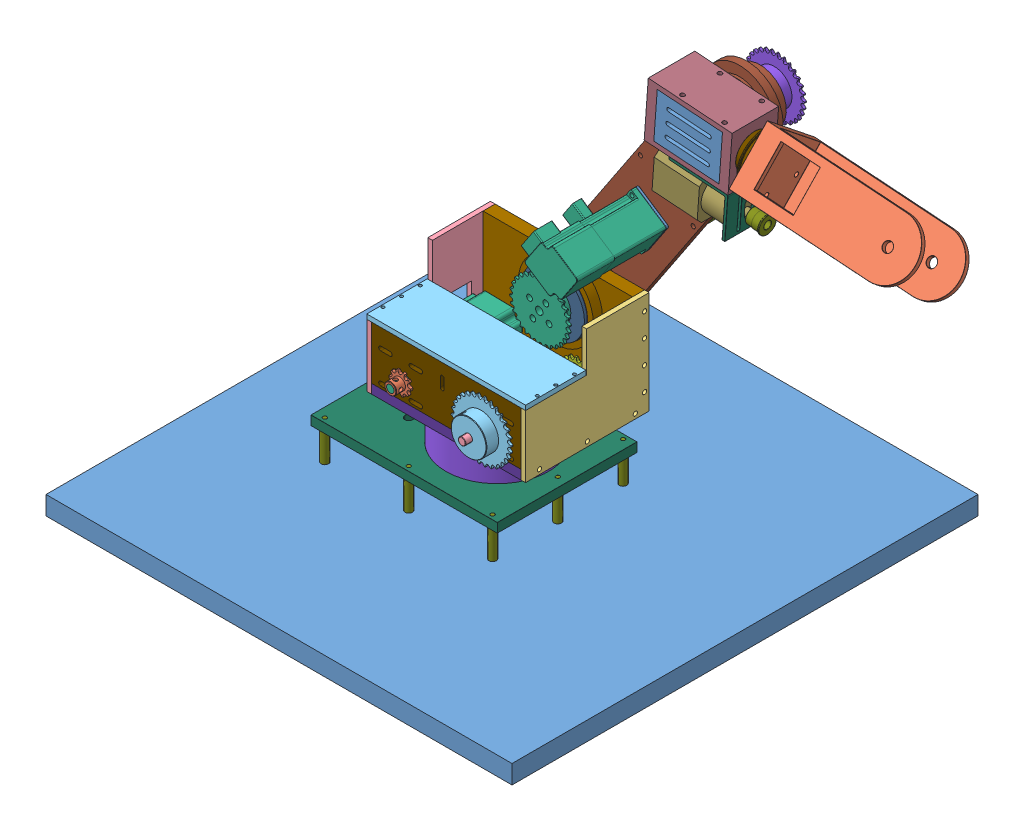
SolidWorks assembly joint 1 assembly, configuration Default. Lengths in mm.
Overall size (663.35 621.65 500).
151 component instances, 59 part files, 55 mates.
Components (placement in the parent):
- base wood-1: base wood [Default] at (212.0824 390.1321 436.9569) size (500 20 500)
- gear hold on joint 1-1: gear hold on joint 1 [Default] at (112.0824 407.1321 436.9569) x (-0.002512 0 0.999997) z (-0.999997 0 -0.002512) size (42 3 42)
- gear100w_cylinder-1: gear100w_cylinder [Default] at (112.0824 385.1321 436.9569) x (0.951917 0 -0.306357) z (0.306357 0 0.951917) size (14 51 14)
- Base holding motor-1: Base holding motor [Default] at (112.0824 410.1321 436.9569) size (70 5 62)
- gear servo 100W-1: gear servo 100W [Default] at (112.0824 407.1321 436.9569) x (-0.002512 0 0.999997) z (-0.999997 0 -0.002512) size (42 67 42)
- mitsu 100W motor-1: mitsu 100W motor [Default] at (92.1327 338.1321 416.9067) x (-0.002512 0 0.999997) z (-0.999997 0 -0.002512) size (42 121 56)
- 15teeths_14mm-1: 15teeths_14mm [25B15] at (112.0824 436.1321 436.9569) size (33.63 12.7 33.47)
- turret cover-1: turret cover [Default] at (196.2679 462.6321 436.9569) size (110 41 110)
- 51113-1: 51113 [Default] at (196.2679 474.1321 436.9569) x (0.999998 0 -0.002197) z (0.002197 0 0.999998) size (90 18 90)
  - 51113_3-1: 51113_3 [Default] at (-36.8829 9 -13.4243) x (0 -1 0) z (0 0 1) size (9 9 9)
  - 51113_3-2: 51113_3 [Default] at (-30.0672 9 -25.2294) x (0 -1 0) z (0 0 1) size (9 9 9)
  - 51113_3-3: 51113_3 [Default] at (-19.625 9 -33.9915) x (0 -1 0) z (0 0 1) size (9 9 9)
  - 51113_3-4: 51113_3 [Default] at (-6.8157 9 -38.6537) x (0 -1 0) z (0 0 1) size (9 9 9)
  - 51113_3-5: 51113_3 [Default] at (6.8157 9 -38.6537) x (0 -1 0) z (0 0 1) size (9 9 9)
  - 51113_3-6: 51113_3 [Default] at (19.625 9 -33.9915) x (0 -1 0) z (0 0 1) size (9 9 9)
  - 51113_3-7: 51113_3 [Default] at (30.0672 9 -25.2294) x (0 -1 0) z (0 0 1) size (9 9 9)
  - 51113_3-8: 51113_3 [Default] at (36.8829 9 -13.4243) x (0 -1 0) z (0 0 1) size (9 9 9)
  - 51113_3-9: 51113_3 [Default] at (39.25 9 0) x (0 -1 0) z (0 0 1) size (9 9 9)
  - 51113_3-10: 51113_3 [Default] at (36.8829 9 13.4243) x (0 -1 0) z (0 0 1) size (9 9 9)
  - 51113_3-11: 51113_3 [Default] at (30.0672 9 25.2294) x (0 -1 0) z (0 0 1) size (9 9 9)
  - 51113_3-12: 51113_3 [Default] at (19.625 9 33.9915) x (0 -1 0) z (0 0 1) size (9 9 9)
  - 51113_3-13: 51113_3 [Default] at (6.8157 9 38.6537) x (0 -1 0) z (0 0 1) size (9 9 9)
  - 51113_3-14: 51113_3 [Default] at (-6.8157 9 38.6537) x (0 -1 0) z (0 0 1) size (9 9 9)
  - 51113_3-15: 51113_3 [Default] at (-19.625 9 33.9915) x (0 -1 0) z (0 0 1) size (9 9 9)
  - 51113_3-16: 51113_3 [Default] at (-30.0672 9 25.2294) x (0 -1 0) z (0 0 1) size (9 9 9)
  - 51113_3-17: 51113_3 [Default] at (-36.8829 9 13.4243) x (0 -1 0) z (0 0 1) size (9 9 9)
  - 51113_3-18: 51113_3 [Default] at (-39.25 9 0) x (0 -1 0) z (0 0 1) size (9 9 9)
  - 51113_22-1: 51113_22 [Default] at (0 13 0) x (0 1 0) z (0 0 1) size (5 90 90)
  - 51113_24-1: 51113_24 [Default] at origin size (90 5 90)
- B6812VV-1: B6812VV [Default] at (196.2679 474.1321 436.9569) x (0 -1 0) z (1 0 0) size (10 78 78)
- B6812VV-2: B6812VV [Default] at (196.2679 451.1321 436.9569) x (0 1 0) z (0 0 1) size (10 78 78)
- joint 1 turret-1: joint 1 turret [Default] at (196.2679 451.1321 436.9569) x (0.160249 0 -0.987077) z (0 1 0) size (77 77 57)
- 45teeths_turret joint 1-1: 45teeths_turret joint 1 [25B45] at (196.2679 433.3381 436.9569) x (0.160249 0 -0.987077) z (-0.987077 0 -0.160249) size (94.59 2.79 94.53)
- Base Joint 1-1: Base Joint 1 [Default] at (196.2679 441.1321 436.9569) size (200 10 150)
- hold up base joint 1-1: hold up base joint 1 [Default] at (261.2679 410.1321 506.9569) size (8 61 8)
- hold up base joint 1-2: hold up base joint 1 [Default] at (171.2679 410.1321 366.9569) size (8 61 8)
- hold up base joint 1-3: hold up base joint 1 [Default] at (81.2679 410.1321 366.9569) size (8 61 8)
- hold up base joint 1-4: hold up base joint 1 [Default] at (171.2679 410.1321 506.9569) size (8 61 8)
- hold up base joint 1-5: hold up base joint 1 [Default] at (261.2679 410.1321 436.9569) size (8 61 8)
- hold up base joint 1-6: hold up base joint 1 [Default] at (261.2679 410.1321 366.9569) size (8 61 8)
- hold up base joint 1-7: hold up base joint 1 [Default] at (81.2679 410.1321 436.9569) size (8 61 8)
- hold up base joint 1-8: hold up base joint 1 [Default] at (81.2679 410.1321 506.9569) size (8 61 8)
- joint 2 assembly ver2 -1: joint 2 assembly ver2  [Default] at (57.2608 443.2302 488.4776) x (-0.002197 0 -0.999998) z (0.999998 0 -0.002197) size (231.98 388.16 503.96)
  - joint 1 turret cap-1: joint 1 turret cap [Default] at (51.2152 49.9019 139.1199) size (130 15 160)
  - hold servo and gear-1: hold servo and gear [Default] at (-13.7848 80.9681 149.1199) x (0 0 -1) z (0 -1 0) size (160 5 57.13)
  - mitsu 100W motor-1: mitsu 100W motor [Default] at (-0.7848 101.743 86.2077) x (0 -0.999767 -0.0216) z (0 0.0216 -0.999767) size (42 121 56)
  - on the servo 200W-1: on the servo 200W [Default] at (-8.7848 81.3156 105.771) x (0 0.0216 -0.999767) z (0 -0.999767 -0.0216) size (40 3 40)
  - 25B10 fixed-1: 25B10 fixed [25B10] at (-17.5848 81.3156 105.771) x (0 0.053959 -0.998543) z (0 -0.998543 -0.053959) size (23.35 12.7 22.79)
  - gear 100W-1: gear 100W [Default] at (55.2152 81.0007 192.7913) x (0 0 -1) z (0 -1 0) size (42 67 42)
  - long cylinder-1: long cylinder [Default] at (-0.7848 81.0007 192.7913) x (0 -0.902756 0.430154) z (0 -0.430154 -0.902756) size (14 125 14)
  - SP25B30 fixede-1: SP25B30 fixede [25B30] at (-17.5848 81.0007 192.7913) x (0 -0.851981 0.523572) z (0 0.523572 0.851981) size (64.23 15.88 63.98)
  - 15teeths_14mm-1: 15teeths_14mm [25B15] at (84.2152 81.0007 192.7913) x (0 -0.225508 -0.974241) z (0 -0.974241 0.225508) size (33.63 12.7 33.47)
  - 30teeths_turret-1: 30teeths_turret [25B30] at (78.4212 124.9019 157.0409) x (0 -0.554392 0.832255) z (0 -0.832255 -0.554392) size (64.23 14.79 63.98)
  - HR32909J-1: HR32909J [Default] at (96.2152 124.9019 157.0409) x (-1 0 0) z (0 -1 0) size (15 68 68)
    - HR32909J_3-1: HR32909J_3 [Default] at origin size (12 68 68)
    - HR32909J_5-1: HR32909J_5 [Default] at origin size (15 63.56 63.56)
  - HR32909J-2: HR32909J [Default] at (128.2152 124.9019 157.0409) size (15 68 68)
    - HR32909J_3-1: HR32909J_3 [Default] at origin size (12 68 68)
    - HR32909J_5-1: HR32909J_5 [Default] at origin size (15 63.56 63.56)
  - turret cover joint 2-2: turret cover joint 2 [Default] at (111.2152 124.9019 157.0409) x (0 0 1) z (0 -1 0) size (160 31 115)
  - Joint2 turret-2: Joint2 turret [Default] at (132.2152 124.9019 157.0409) x (0 0.832255 0.554392) z (-1 0 0) size (67 67 39)
  - joint 2 arm-2: joint 2 arm [Default] at (137.2152 124.9019 157.0409) x (0 0.832255 0.554392) z (0 -0.554392 0.832255) size (374 25 80)
  - mitsu 100W motor-2: mitsu 100W motor [Default] at (121.2152 210.8927 190.2911) x (0 0.832255 0.554392) z (0 0.554392 -0.832255) size (42 121 56)
  - on the servo 200W-2: on the servo 200W [Default] at (129.2152 216.4499 218.0241) x (0 0.832255 0.554392) z (0 -0.554392 0.832255) size (40 3 40)
  - SP25B30 fixed with bearing-1: SP25B30 fixed with bearing [25B30] at (150.7152 278.8691 259.6035) x (0 0.696244 0.717805) z (0 -0.717805 0.696244) size (64.23 15.88 63.98)
  - 25B10 fixed-3: 25B10 fixed [25B10] at (172.2902 278.8691 259.6035) x (0 -0.696244 -0.717805) z (0 -0.717805 0.696244) size (23.35 12.7 22.79)
  - hold bearing tang dua-2: hold bearing tang dua [Default] at (129.2152 278.8691 259.6035) x (0 -0.832255 -0.554392) z (0 -0.554392 0.832255) size (30 8 30)
  - BB_688_B180_10_ES-1: BB_688_B180_10_ES [Default] at (153.2152 278.8691 259.6035) x (1 0 0) z (0 0.696244 0.717805) size (5 16 16)
    - BB_688_B180_10_ES_3-1: BB_688_B180_10_ES_3 [Default] at (0 3.7394 -4.689) x (-1 0 0) z (0 0 1) size (3 3 3)
    - BB_688_B180_10_ES_3-2: BB_688_B180_10_ES_3 [Default] at (0 -1.3346 -5.8471) x (-1 0 0) z (0 0 1) size (3 3 3)
    - BB_688_B180_10_ES_3-3: BB_688_B180_10_ES_3 [Default] at (0 -5.4036 -2.6022) x (-1 0 0) z (0 0 1) size (3 3 3)
    - BB_688_B180_10_ES_3-4: BB_688_B180_10_ES_3 [Default] at (0 -5.4036 2.6022) x (-1 0 0) z (0 0 1) size (3 3 3)
    - BB_688_B180_10_ES_3-5: BB_688_B180_10_ES_3 [Default] at (0 -1.3346 5.8471) x (-1 0 0) z (0 0 1) size (3 3 3)
    - BB_688_B180_10_ES_3-6: BB_688_B180_10_ES_3 [Default] at (0 3.7394 4.689) x (-1 0 0) z (0 0 1) size (3 3 3)
    - BB_688_B180_10_ES_3-7: BB_688_B180_10_ES_3 [Default] at (0 5.9975 0) x (-1 0 0) z (0 0 1) size (3 3 3)
    - BB_688_B180_10_ES_11-1: BB_688_B180_10_ES_11 [Default] x (1 0 0) z (0 -0.781831 0.62349) size (0.75 1.78 2.65)
    - BB_688_B180_10_ES_11-2: BB_688_B180_10_ES_11 [Default] x (1 0 0) z (0 -0.974928 -0.222521) size (0.75 1.78 2.65)
    - BB_688_B180_10_ES_11-3: BB_688_B180_10_ES_11 [Default] x (1 0 0) z (0 -0.433884 -0.900969) size (0.75 1.78 2.65)
    - BB_688_B180_10_ES_11-4: BB_688_B180_10_ES_11 [Default] x (1 0 0) z (0 0.433884 -0.900969) size (0.75 1.78 2.65)
    - BB_688_B180_10_ES_11-5: BB_688_B180_10_ES_11 [Default] x (1 0 0) z (0 0.974928 -0.222521) size (0.75 1.78 2.65)
    - BB_688_B180_10_ES_11-6: BB_688_B180_10_ES_11 [Default] x (1 0 0) z (0 0.781831 0.62349) size (0.75 1.78 2.65)
    - BB_688_B180_10_ES_11-7: BB_688_B180_10_ES_11 [Default] at origin size (0.75 1.78 2.65)
    - BB_688_B180_10_ES_19-1: BB_688_B180_10_ES_19 [Default] x (-1 0 0) z (0 0 1) size (5 10.66 10.66)
    - BB_688_B180_10_ES_21-1: BB_688_B180_10_ES_21 [Default] at origin size (5 16 16)
  - 608VV-3: 608VV [Default] at (122.2152 278.8691 259.6035) x (1 0 0) z (0 0.832255 0.554392) size (7 22 22)
    - 608VV_3-1: 608VV_3 [Default] at origin size (0.29 19 19)
    - 608VV_5-1: 608VV_5 [Default] at (3.5 5.3033 5.3033) x (1 0 0) z (0 -1 0) size (4.2 4.2 4.2)
    - 608VV_5-2: 608VV_5 [Default] at (3.5 7.5 0) x (1 0 0) z (0 -1 0) size (4.2 4.2 4.2)
    - 608VV_5-3: 608VV_5 [Default] at (3.5 5.3033 -5.3033) x (1 0 0) z (0 -1 0) size (4.2 4.2 4.2)
    - 608VV_5-4: 608VV_5 [Default] at (3.5 0 -7.5) x (1 0 0) z (0 -1 0) size (4.2 4.2 4.2)
    - 608VV_5-5: 608VV_5 [Default] at (3.5 -5.3033 -5.3033) x (1 0 0) z (0 -1 0) size (4.2 4.2 4.2)
    - 608VV_5-6: 608VV_5 [Default] at (3.5 -7.5 0) x (1 0 0) z (0 -1 0) size (4.2 4.2 4.2)
    - 608VV_5-7: 608VV_5 [Default] at (3.5 -5.3033 5.3033) x (1 0 0) z (0 -1 0) size (4.2 4.2 4.2)
    - 608VV_5-8: 608VV_5 [Default] at (3.5 0 7.5) x (1 0 0) z (0 -1 0) size (4.2 4.2 4.2)
    - 608VV_14-1: 608VV_14 [Default] at (0.77 0 0) x (-1 0 0) z (0 -1 0) size (0.29 19 19)
    - 608VV_16-1: 608VV_16 [Default] x (1 0 0) z (0 -1 0) size (7 12.14 12.14)
    - 608VV_18-1: 608VV_18 [Default] at origin size (7 22 22)
  - cylinder on joint 2 arm-1: cylinder on joint 2 arm [Default] at (121.1976 278.8691 259.6035) x (0 -0.608732 -0.793376) z (0 -0.793376 0.608732) size (8 70 8)
  - 25B10 fixed-4: 25B10 fixed [25B10] at (150.7152 216.4499 218.0241) x (0 -0.926055 0.377389) z (0 0.377389 0.926055) size (23.35 12.7 22.79)
  - tang dua joint 3-1: tang dua joint 3 [Default] at (182.4252 283.0304 262.3755) x (0 0.832255 0.554392) z (0 -0.554392 0.832255) size (70 5 78)
  - luc giac-5: luc giac [Default] at (137.2152 272.7508 214.6751) x (0 -1 0) z (0 0 1) size (6.93 43.21 8)
  - luc giac-6: luc giac [Default] at (137.2152 284.9874 304.532) x (0 -1 0) z (0 0 1) size (6.93 43.21 8)
  - luc giac-7: luc giac [Default] at (137.2152 322.6861 247.9386) x (0 -1 0) z (0 0 1) size (6.93 43.21 8)
  - luc giac-8: luc giac [Default] at (137.2152 235.0521 271.2684) x (0 -0.999991 0.004217) z (0 0.004217 0.999991) size (6.93 43.21 8)
  - sprokets joint 3 turret 30 teeth-1: sprokets joint 3 turret 30 teeth [25B30] at (169.4962 370.4172 320.5867) x (0 0.997318 0.073185) z (0 0.073185 -0.997318) size (64.23 15.88 63.98)
  - joint3 turret-1: joint3 turret [Default] at (121.2152 370.4172 320.5867) x (0 -0.073185 0.997318) z (0 0.997318 0.073185) size (46 32 46)
  - HR32906J-1: HR32906J [Default] at (151.2152 370.4172 320.5867) size (12 47 47)
    - HR32906J_3-1: HR32906J_3 [Default] at origin size (9 47 47)
    - HR32906J_5-1: HR32906J_5 [Default] at origin size (12 43.2 43.2)
  - HR32906J-2: HR32906J [Default] at (125.2152 370.4172 320.5867) x (-1 0 0) z (0 -1 0) size (12 47 47)
    - HR32906J_3-1: HR32906J_3 [Default] at origin size (9 47 47)
    - HR32906J_5-1: HR32906J_5 [Default] at origin size (12 43.2 43.2)
  - stepnerma42 with gear-1: stepnerma42 with gear [Default] at (99.2152 313.2981 279.1291) x (1 -0.000151 -0.000011) z (0 -0.073185 0.997318) size (42 42 97)
  - joint 4 turret-1: joint 4 turret [Default] at (74.2152 370.4172 320.5867) x (0 0.073185 -0.997318) z (0 -0.997318 -0.073185) size (90 50 60)
  - bearing_stretch-1: bearing_stretch [Default] at (99.2152 372.8323 287.6752) x (1 0 0) z (0 0.997318 0.073185) size (30 2 30)
  - 608VV-4: 608VV [Default] at (99.2152 372.9787 285.6806) x (0 0.073185 -0.997318) z (1 0 0) size (7 22 22)
    - 608VV_3-1: 608VV_3 [Default] at origin size (0.29 19 19)
    - 608VV_5-1: 608VV_5 [Default] at (3.5 5.3033 5.3033) x (1 0 0) z (0 -1 0) size (4.2 4.2 4.2)
    - 608VV_5-2: 608VV_5 [Default] at (3.5 7.5 0) x (1 0 0) z (0 -1 0) size (4.2 4.2 4.2)
    - 608VV_5-3: 608VV_5 [Default] at (3.5 5.3033 -5.3033) x (1 0 0) z (0 -1 0) size (4.2 4.2 4.2)
    - 608VV_5-4: 608VV_5 [Default] at (3.5 0 -7.5) x (1 0 0) z (0 -1 0) size (4.2 4.2 4.2)
    - 608VV_5-5: 608VV_5 [Default] at (3.5 -5.3033 -5.3033) x (1 0 0) z (0 -1 0) size (4.2 4.2 4.2)
    - 608VV_5-6: 608VV_5 [Default] at (3.5 -7.5 0) x (1 0 0) z (0 -1 0) size (4.2 4.2 4.2)
    - 608VV_5-7: 608VV_5 [Default] at (3.5 -5.3033 5.3033) x (1 0 0) z (0 -1 0) size (4.2 4.2 4.2)
    - 608VV_5-8: 608VV_5 [Default] at (3.5 0 7.5) x (1 0 0) z (0 -1 0) size (4.2 4.2 4.2)
    - 608VV_14-1: 608VV_14 [Default] at (0.77 0 0) x (-1 0 0) z (0 -1 0) size (0.29 19 19)
    - 608VV_16-1: 608VV_16 [Default] x (1 0 0) z (0 -1 0) size (7 12.14 12.14)
    - 608VV_18-1: 608VV_18 [Default] at origin size (7 22 22)
  - 608VV-5: 608VV [Default] at (99.2152 367.3434 362.4741) x (0 0.073185 -0.997318) z (0 -0.997318 -0.073185) size (7 22 22)
    - 608VV_3-1: 608VV_3 [Default] at origin size (0.29 19 19)
    - 608VV_5-1: 608VV_5 [Default] at (3.5 5.3033 5.3033) x (1 0 0) z (0 -1 0) size (4.2 4.2 4.2)
    - 608VV_5-2: 608VV_5 [Default] at (3.5 7.5 0) x (1 0 0) z (0 -1 0) size (4.2 4.2 4.2)
    - 608VV_5-3: 608VV_5 [Default] at (3.5 5.3033 -5.3033) x (1 0 0) z (0 -1 0) size (4.2 4.2 4.2)
    - 608VV_5-4: 608VV_5 [Default] at (3.5 0 -7.5) x (1 0 0) z (0 -1 0) size (4.2 4.2 4.2)
    - 608VV_5-5: 608VV_5 [Default] at (3.5 -5.3033 -5.3033) x (1 0 0) z (0 -1 0) size (4.2 4.2 4.2)
    - 608VV_5-6: 608VV_5 [Default] at (3.5 -7.5 0) x (1 0 0) z (0 -1 0) size (4.2 4.2 4.2)
    - 608VV_5-7: 608VV_5 [Default] at (3.5 -5.3033 5.3033) x (1 0 0) z (0 -1 0) size (4.2 4.2 4.2)
    - 608VV_5-8: 608VV_5 [Default] at (3.5 0 7.5) x (1 0 0) z (0 -1 0) size (4.2 4.2 4.2)
    - 608VV_14-1: 608VV_14 [Default] at (0.77 0 0) x (-1 0 0) z (0 -1 0) size (0.29 19 19)
    - 608VV_16-1: 608VV_16 [Default] x (1 0 0) z (0 -1 0) size (7 12.14 12.14)
    - 608VV_18-1: 608VV_18 [Default] at origin size (7 22 22)
  - bearing_stretch-2: bearing_stretch [Default] at (99.2152 367.8557 355.4928) x (0 0.997318 0.073185) z (-1 0 0) size (30 2 30)
  - stepper hold joint 4-1: stepper hold joint 4 [Default] at (99.2152 317.2701 361.641) x (1 0 0) z (0 0.997318 0.073185) size (50 63 45)
  - pulley_gt2_20_5-1: pulley_gt2_20_5 [Default] at (99.2152 307.0042 364.8984) x (0 -0.073185 0.997318) z (0.69037 0.721516 0.052946) size (16 19 19)
  - cylinder joint 4-1: cylinder joint 4 [Default] at (99.2152 372.9908 285.5148) x (0.844862 0.53355 0.039153) z (0.534984 -0.842596 -0.061831) size (8 100 8)
  - pulley_gt2_80_8-2: pulley_gt2_80_8 [Default] at (99.2152 366.4408 374.7748) x (0 -0.073185 0.997318) z (-0.775768 0.629326 0.046181) size (20 54 54)
  - side part joint 4-1: side part joint 4 [Default] at (74.2152 370.4172 320.5867) x (0 0.073185 -0.997318) z (0 -0.997318 -0.073185) size (70 10 50)
  - joint 5 holding-2: joint 5 holding [Default] at (99.2152 365.6723 385.2466) x (-0.775768 0.629326 0.046181) z (0.631018 0.773688 0.056775) size (70 180 60)
  - joint 2 cover-2: joint 2 cover [Default] at (51.8286 104.1686 229.1199) x (1 0 0) z (0 -1 0) size (133 5 110)
  - joint 2 cover part 2-2: joint 2 cover part 2 [Default] at (51.8286 104.1686 64.1199) x (1 0 0) z (0 -1 0) size (133 5 110)
  - joint 2 cover part 3-2: joint 2 cover part 3 [Default] at (18.7152 116.9019 149.1199) x (0 0 -1) z (1 0 0) size (170 5 65)
Mates (geometry in assembly coordinates):
- Coincident1: coincident anti-aligned: plane of base wood-1 through (212.0824 410.1321 436.9569) normal (0 1 0); plane of Base holding motor-1 through (112.0824 410.1321 436.9569) normal (0 -1 0)
- Concentric1: concentric aligned: cylinder of base wood-1 through (84.0104 410.1321 412.0931) axis (0 -1 0) radius 3; cylinder of Base holding motor-1 through (84.0104 415.1321 412.0931) axis (0 -1 0) radius 3
- Concentric2: concentric aligned: cylinder of base wood-1 through (140.1545 410.1321 461.8207) axis (0 -1 0) radius 3; cylinder of Base holding motor-1 through (140.1545 415.1321 461.8207) axis (0 -1 0) radius 3
- Concentric3: concentric aligned: cylinder of base wood-1 through (84.0104 410.1321 461.8207) axis (0 -1 0) radius 3; cylinder of Base holding motor-1 through (84.0104 415.1321 461.8207) axis (0 -1 0) radius 3
- Coincident2: coincident anti-aligned: plane of gear hold-1 through (112.0824 407.1321 436.9569) normal (0 -1 0); plane of gear 100W-1 through (112.0824 407.1321 436.9569) normal (0 1 0)
- Concentric4: concentric aligned: cylinder of gear hold-1 through (112.0824 410.1321 436.9569) axis (0 -1 0) radius 15; cylinder of gear 100W-1 through (112.0824 410.1321 436.9569) axis (0 -1 0) radius 15
- Concentric5: concentric anti-aligned: cylinder of gear hold-1 through (128.3867 410.1321 420.7343) axis (0 -1 0) radius 2.25; cylinder of gear 100W-1 through (128.3867 403.1321 420.7343) axis (0 1 0) radius 2.25
- Concentric6: concentric anti-aligned: cylinder of gear hold-1 through (95.7782 410.1321 453.1794) axis (0 -1 0) radius 2.25; cylinder of gear 100W-1 through (95.7782 403.1321 453.1794) axis (0 1 0) radius 2.25
- Concentric7: concentric anti-aligned: cylinder of gear100w_cylinder-1 through (112.0824 436.1321 436.9569) axis (0 -1 0) radius 7; cylinder of gear 100W-1 through (112.0824 328.3331 436.9569) axis (0 1 0) radius 7
- Distance1: distance = 26 mm aligned: plane of gear100w_cylinder-1 through (112.0824 436.1321 436.9569) normal (0 1 0); plane of gear 100W-1 through (112.0824 410.1321 436.9569) normal (0 1 0)
- Coincident4: coincident anti-aligned: plane of gear hold-1 through (112.0824 410.1321 436.9569) normal (0 1 0); plane of Base holding motor-1 through (112.0824 410.1321 436.9569) normal (0 -1 0)
- Concentric8: concentric aligned: cylinder of gear100w_cylinder-1 through (112.0824 436.1321 436.9569) axis (0 -1 0) radius 7; cylinder of Base holding motor-1 through (112.0824 415.1321 436.9569) axis (0 -1 0) radius 7
- Parallel2: parallel aligned: cylinder of gear hold-1 through (95.7782 410.1321 453.1794) axis (0 -1 0) radius 2.25; cylinder of Base holding motor-1 through (128.3704 415.1321 453.2448) axis (0 -1 0) radius 2.25
- Parallel3: parallel aligned: cylinder of gear hold-1 through (128.305 410.1321 453.2611) axis (0 -1 0) radius 2.25; cylinder of Base holding motor-1 through (128.3704 415.1321 420.6689) axis (0 -1 0) radius 2.25
- Coincident5: coincident anti-aligned: plane of gear 100W-1 through (112.0824 343.1321 436.9569) normal (0 -1 0); plane of mitsu 100W motor-1 through (130.0372 343.1321 455.002) normal (0 1 0)
- Concentric13: concentric aligned: cylinder of gear 100W-1 through (112.0824 348.1321 436.9569) axis (0 -1 0) radius 15; cylinder of mitsu 100W motor-1 through (112.0824 345.6321 436.9569) axis (0 -1 0) radius 15
- Concentric14: concentric aligned: cylinder of gear100w_cylinder-1 through (112.0824 436.1321 436.9569) axis (0 -1 0) radius 7; cylinder of 15teeths_14mm-1 through (112.0824 437.4321 436.9569) axis (0 -1 0) radius 7
- Coincident6: coincident aligned: plane of gear100w_cylinder-1 through (112.0824 436.1321 436.9569) normal (0 1 0); plane of 15teeths_14mm-1 through (112.0824 436.1321 436.9569) normal (0 1 0)
- Coincident7: coincident anti-aligned: plane of turret cover-1 through (196.2679 464.1321 436.9569) normal (0 1 0); plane of B6812VV-1 through (196.2679 464.1321 406.6569) normal (0 -1 0)
- Concentric15: concentric anti-aligned: cylinder of turret cover-1 through (196.2679 446.1321 436.9569) axis (0 1 0) radius 39; cylinder of B6812VV-1 through (196.2679 464.1321 436.9569) axis (0 -1 0) radius 39
- Coincident8: coincident anti-aligned: plane of turret cover-1 through (196.2679 474.1321 436.9569) normal (0 1 0); plane of 51113-1/51113_24-1 through (152.268 474.1321 437.0536) normal (0 -1 0)
- Concentric16: concentric aligned: cylinder of turret cover-1 through (196.2679 446.1321 436.9569) axis (0 1 0) radius 45; cylinder of 51113-1/51113_24-1 through (196.2679 479.1321 436.9569) axis (0 1 0) radius 45
- Coincident9: coincident anti-aligned: plane of turret cover-1 through (196.2679 461.1321 436.9569) normal (0 -1 0); plane of B6812VV-2 through (165.9679 461.1321 436.9569) normal (0 1 0)
- Concentric17: concentric aligned: cylinder of turret cover-1 through (196.2679 446.1321 436.9569) axis (0 1 0) radius 39; cylinder of B6812VV-2 through (196.2679 461.1321 436.9569) axis (0 1 0) radius 39
- Concentric18: concentric aligned: cylinder of B6812VV-1 through (196.2679 464.1321 436.9569) axis (0 -1 0) radius 30; cylinder of joint 1 turret-1 through (196.2679 493.1321 436.9569) axis (0 -1 0) radius 30
- Coincident10: coincident anti-aligned: plane of B6812VV-2 through (163.3879 451.1321 436.9569) normal (0 -1 0); plane of joint 1 turret-1 through (196.2679 451.1321 436.9569) normal (0 1 0)
- Coincident11: coincident anti-aligned: plane of joint 1 turret-1 through (196.2679 436.1321 436.9569) normal (0 -1 0); plane of 45teeths_turret joint 1-1 through (203.5617 436.1321 392.0296) normal (0 1 0)
- Concentric19: concentric anti-aligned: cylinder of joint 1 turret-1 through (200.2741 446.1321 412.28) axis (0 -1 0) radius 3; cylinder of 45teeths_turret joint 1-1 through (200.2741 426.1321 412.28) axis (0 1 0) radius 3
- Concentric20: concentric anti-aligned: cylinder of joint 1 turret-1 through (220.9448 446.1321 440.9631) axis (0 -1 0) radius 3; cylinder of 45teeths_turret joint 1-1 through (220.9448 426.1321 440.9631) axis (0 1 0) radius 3
- Coincident13: coincident anti-aligned: plane of turret cover-1 through (196.2679 446.1321 436.9569) normal (0 -1 0); plane of Base Upper Joint 1-1 through (196.2679 446.1321 436.9569) normal (0 1 0)
- Concentric24: concentric anti-aligned: cylinder of turret cover-1 through (196.2679 446.1321 436.9569) axis (0 1 0) radius 55; cylinder of Base Upper Joint 1-1 through (196.2679 451.1321 436.9569) axis (0 -1 0) radius 55
- Parallel4: parallel anti-aligned: cylinder of turret cover-1 through (243.2679 456.1321 436.9569) axis (0 -1 0) radius 2; cylinder of Base Upper Joint 1-1 through (243.0179 441.1321 436.9569) axis (0 1 0) radius 2
- Coincident14: coincident aligned: plane of 15teeths_14mm-1 through (127.3533 433.3381 436.9569) normal (0 -1 0); plane of 45teeths_turret joint 1-1 through (196.2679 433.3381 436.9569) normal (0 -1 0)
- Concentric26: concentric anti-aligned: cylinder of base wood-1 through (261.2679 390.1321 366.9569) axis (0 1 0) radius 2; cylinder of Base Upper Joint 1-1 through (261.2679 451.1321 366.9569) axis (0 -1 0) radius 2
- Concentric27: concentric anti-aligned: cylinder of base wood-1 through (81.2679 390.1321 506.9569) axis (0 1 0) radius 2; cylinder of Base Upper Joint 1-1 through (81.2679 451.1321 506.9569) axis (0 -1 0) radius 2
- Concentric28: concentric anti-aligned: cylinder of base wood-1 through (261.2679 390.1321 506.9569) axis (0 1 0) radius 2; cylinder of Base Upper Joint 1-1 through (261.2679 451.1321 506.9569) axis (0 -1 0) radius 2
- Coincident15: coincident anti-aligned: plane of Base Joint 1-1 through (196.2679 441.1321 436.9569) normal (0 -1 0); plane of hold up base joint 1-3 through (81.2679 441.1321 366.9569) normal (0 1 0)
- Concentric29: concentric anti-aligned: cylinder of Base Joint 1-1 through (81.2679 451.1321 366.9569) axis (0 -1 0) radius 2; cylinder of hold up base joint 1-3 through (81.2679 390.1321 366.9569) axis (0 1 0) radius 2
- Concentric30: concentric anti-aligned: cylinder of Base Joint 1-1 through (81.2679 451.1321 506.9569) axis (0 -1 0) radius 2; cylinder of hold up base joint 1-8 through (81.2679 390.1321 506.9569) axis (0 1 0) radius 2
- Coincident16: coincident anti-aligned: plane of Base Joint 1-1 through (196.2679 441.1321 436.9569) normal (0 -1 0); plane of hold up base joint 1-8 through (81.2679 441.1321 506.9569) normal (0 1 0)
- Concentric31: concentric anti-aligned: cylinder of Base Joint 1-1 through (171.2679 451.1321 506.9569) axis (0 -1 0) radius 2; cylinder of hold up base joint 1-4 through (171.2679 390.1321 506.9569) axis (0 1 0) radius 2
- Coincident17: coincident anti-aligned: plane of Base Joint 1-1 through (196.2679 441.1321 436.9569) normal (0 -1 0); plane of hold up base joint 1-4 through (171.2679 441.1321 506.9569) normal (0 1 0)
- Concentric32: concentric anti-aligned: cylinder of Base Joint 1-1 through (81.2679 451.1321 436.9569) axis (0 -1 0) radius 2; cylinder of hold up base joint 1-7 through (81.2679 390.1321 436.9569) axis (0 1 0) radius 2
- Coincident18: coincident anti-aligned: plane of Base Joint 1-1 through (196.2679 441.1321 436.9569) normal (0 -1 0); plane of hold up base joint 1-7 through (81.2679 441.1321 436.9569) normal (0 1 0)
- Concentric33: concentric anti-aligned: cylinder of Base Joint 1-1 through (261.2679 451.1321 506.9569) axis (0 -1 0) radius 2; cylinder of hold up base joint 1-1 through (261.2679 390.1321 506.9569) axis (0 1 0) radius 2
- Coincident19: coincident anti-aligned: plane of Base Joint 1-1 through (196.2679 441.1321 436.9569) normal (0 -1 0); plane of hold up base joint 1-1 through (261.2679 441.1321 506.9569) normal (0 1 0)
- Concentric34: concentric anti-aligned: cylinder of Base Joint 1-1 through (171.2679 451.1321 366.9569) axis (0 -1 0) radius 2; cylinder of hold up base joint 1-2 through (171.2679 390.1321 366.9569) axis (0 1 0) radius 2
- Coincident20: coincident anti-aligned: plane of Base Joint 1-1 through (196.2679 441.1321 436.9569) normal (0 -1 0); plane of hold up base joint 1-2 through (171.2679 441.1321 366.9569) normal (0 1 0)
- Concentric35: concentric anti-aligned: cylinder of Base Joint 1-1 through (261.2679 451.1321 366.9569) axis (0 -1 0) radius 2; cylinder of hold up base joint 1-6 through (261.2679 390.1321 366.9569) axis (0 1 0) radius 2
- Coincident21: coincident anti-aligned: plane of Base Joint 1-1 through (196.2679 441.1321 436.9569) normal (0 -1 0); plane of hold up base joint 1-6 through (261.2679 441.1321 366.9569) normal (0 1 0)
- Concentric36: concentric anti-aligned: cylinder of Base Joint 1-1 through (261.2679 451.1321 436.9569) axis (0 -1 0) radius 2; cylinder of hold up base joint 1-5 through (261.2679 390.1321 436.9569) axis (0 1 0) radius 2
- Coincident22: coincident anti-aligned: plane of Base Joint 1-1 through (196.2679 441.1321 436.9569) normal (0 -1 0); plane of hold up base joint 1-5 through (261.2679 441.1321 436.9569) normal (0 1 0)
- Concentric39: concentric anti-aligned: cylinder of gear 100W-1 through (128.3867 348.1321 420.7343) axis (0 -1 0) radius 2.25; cylinder of mitsu 100W motor-1 through (128.3867 331.7681 420.7343) axis (0 1 0) radius 2.25
- Coincident23: coincident anti-aligned: plane of joint 1 turret-1 through (196.2679 493.1321 436.9569) normal (0 1 0); plane of joint 2 assembly ver2 -1/joint 1 turret cap-1 through (196.2679 493.1321 436.9569) normal (0 -1 0)
- Concentric40: concentric aligned: cylinder of 51113-1/51113_22-1 through (196.2679 492.1321 436.9569) axis (0 1 0) radius 45; cylinder of joint 2 assembly ver2 -1/joint 1 turret cap-1 through (196.2679 488.1321 436.9569) axis (0 1 0) radius 45
